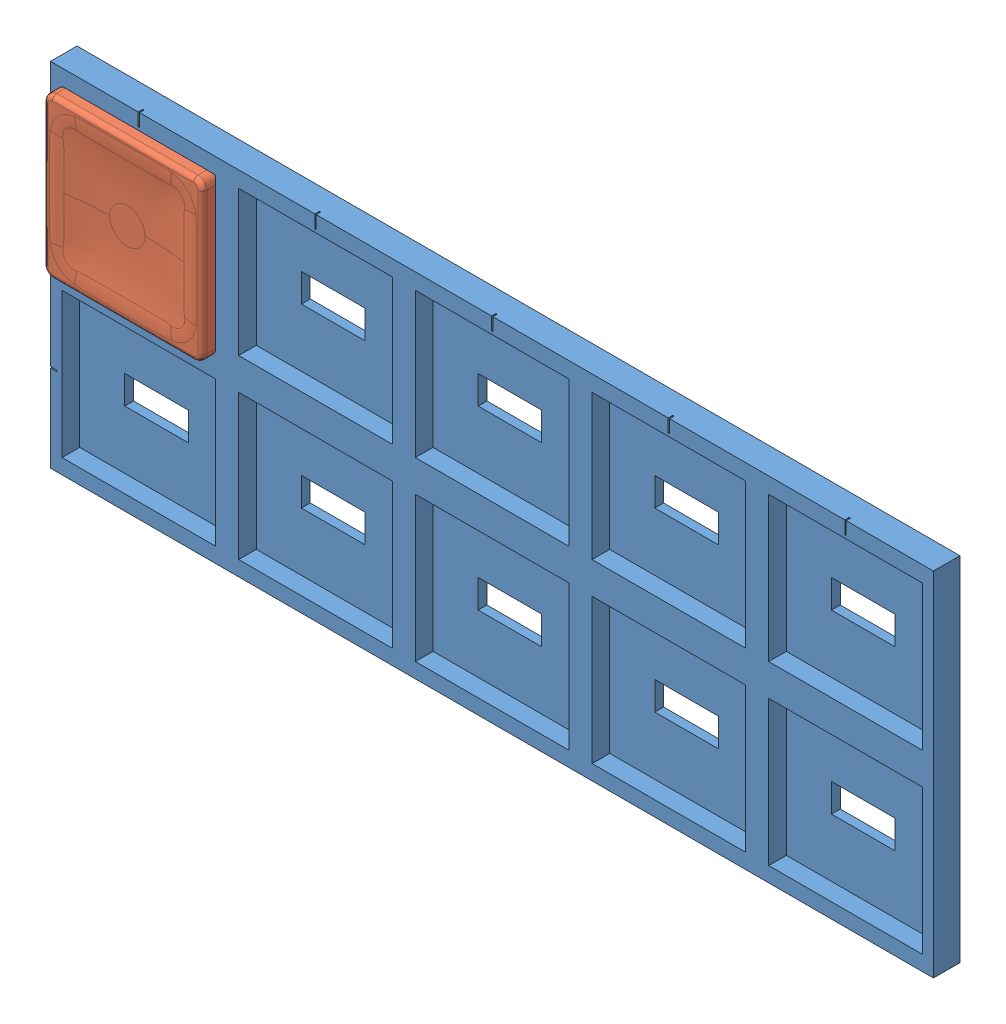
SolidWorks assembly Assemblage1, configuration Défaut. Lengths in mm.
Overall size (99.95 39.9 4.5).
2 component instances, 2 part files, 3 mates.
Components (placement in the parent):
- kailh-engraver-1: kailh-engraver [Défaut] at (-36.2542 10.2633 101.4489) size (99.95 39.9 3)
- Kailh LP Keycap.step-1: Kailh LP Keycap.step [Défaut] at (-36.5542 9.4633 99.4489) x (1 0 0) z (0 -1 0) size (18 4.5 18)
Mates (geometry in assembly coordinates):
- Coïncidente1: coincident: plane of kailh-engraver-1 through (-36.2542 10.2633 99.4489) normal (0 0 1); plane of Kailh LP Keycap.step-1 through (-28.5542 1.4633 99.4489) normal (0 0 -1)
- Coïncidente2: coincident: plane of kailh-engraver-1 through (-44.9542 18.4633 99.4489) normal (0 -1 0); plane of Kailh LP Keycap.step-1 through (-44.5542 18.4633 102.9489) normal (0 1 0)
- Coïncidente3: coincident anti-aligned: plane of kailh-engraver-1 through (-27.5542 2.0633 99.4489) normal (-1 0 0); plane of Kailh LP Keycap.step-1 through (-27.5542 17.4633 102.9489) normal (1 0 0)
